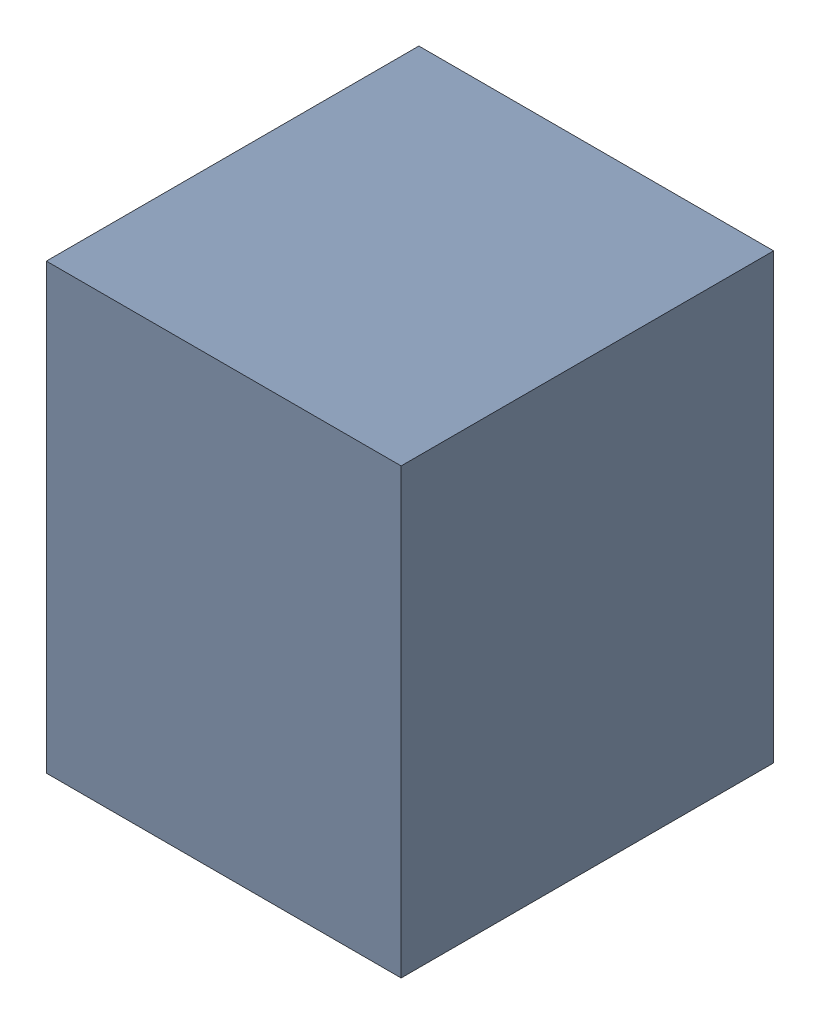
SolidWorks assembly L7, configuration Default. Lengths in mm.
Overall size (2 2.5 2.1).
2 component instances, 1 part files, 0 mates.
Components (placement in the parent):
- 859213232-1: 859213232 [Default] at (122.45 30.15 0) size (2 2.5 2.1)
  - Extruded_3-1: Extruded_3 [Default] at origin size (2 2.5 2.1)
